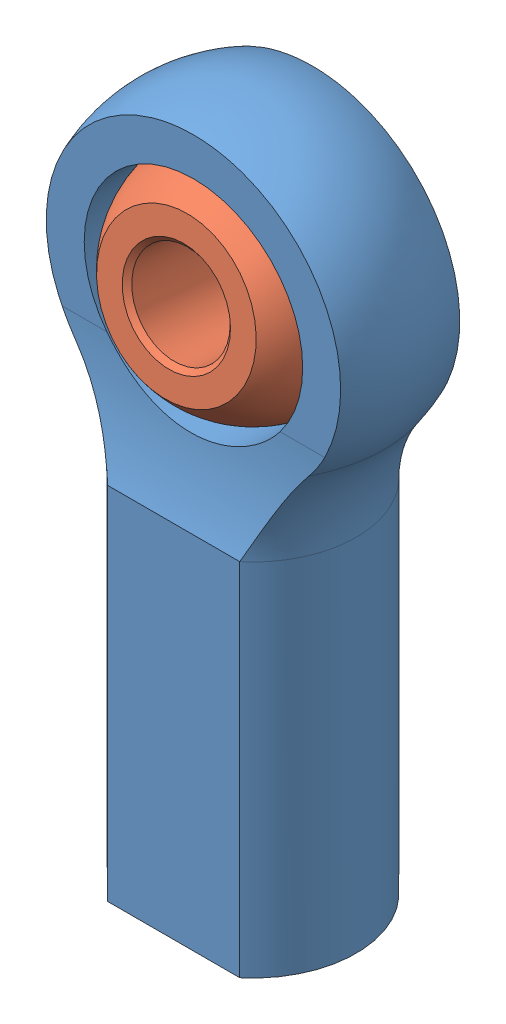
SolidWorks assembly Ball Joint, configuration Default. Lengths in mm.
Overall size (15.88 35.09 10.12).
2 component instances, 2 part files, 1 mates.
Components (placement in the parent):
- Ball Joint Shell-1: Ball Joint Shell [60645K311] at (17.725 15.1966 26.3919) size (15.88 34.93 10.12)
- Ball Joint Ball-1: Ball Joint Ball [Default] at (17.725 29.4841 26.3919) x (-0.02735 -0.117861 -0.992653) z (0.829656 -0.556598 0.043228) size (7.94 11.07 11.07)
Mates (geometry in assembly coordinates):
- Concentric1: concentric: sphere of Ball Joint Shell-1; sphere of Ball Joint Ball-1
